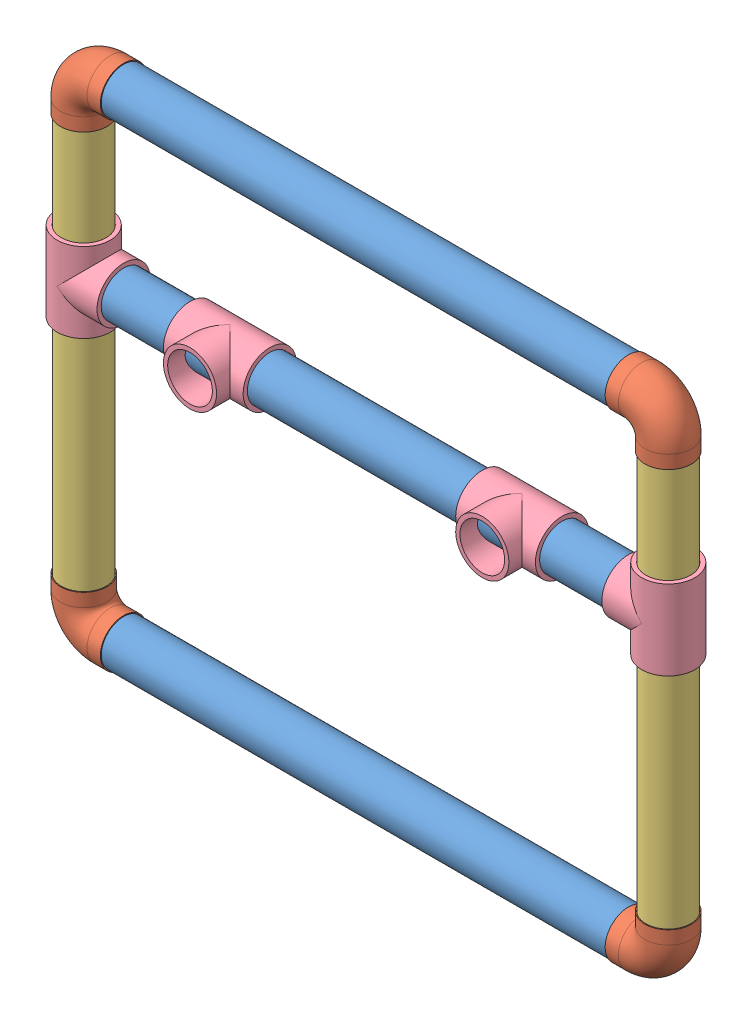
SolidWorks assembly structure_with_tube, configuration Default. Lengths in mm.
Overall size (307.13 254.74 41.21).
13 component instances, 4 part files, 26 mates.
Components (placement in the parent):
- PVC_tube_12in-1: PVC_tube_12in [Default] at (224.9643 139.1096 188.8412) size (254 21.34 21.34)
- PVC_90-1: PVC_90 [Default] at (-23.4538 156.2418 188.8412) size (30.16 30.16 22.23)
- PVC_90-2: PVC_90 [Default] at (220.532 157.3915 188.8412) x (0 1 0) z (0 0 1) size (30.16 30.16 22.23)
- PVC_tube_10in-1: PVC_tube_10in [Default] at (237.6643 151.8096 188.8412) x (0 -1 0) z (0.999303 0 -0.037318) size (203.2 21.34 21.34)
- PVC_90-3: PVC_90 [Default] at (219.3823 350.5774 188.8412) x (-1 0 0) z (0 0 1) size (30.16 30.16 22.23)
- PVC_tube_12in-2: PVC_tube_12in [Default] at (224.9643 367.7096 188.8412) x (1 0 0) z (0 -0.639566 -0.768737) size (254 21.34 21.34)
- PVC_90-4: PVC_90 [Default] at (-24.6035 349.4277 188.8412) x (0 -1 0) z (0 0 1) size (30.16 30.16 22.23)
- PVC_tube_10in-2: PVC_tube_10in [Default] at (-41.7357 355.0096 188.8412) x (0 1 0) z (0.64254 0 -0.766252) size (203.2 21.34 21.34)
- PVC_tee-1: PVC_tee [Default] at (-41.7357 283.3776 188.8412) x (0 1 0) z (0 0 -1) size (38.1 38.88 25.4)
- PVC_tee-2: PVC_tee [Default] at (237.6643 283.3776 188.8412) x (0 1 0) z (0 0 1) size (38.1 38.88 25.4)
- PVC_tee-4: PVC_tee [Default] at (28.1143 283.3776 188.8412) x (1 0 0) z (0 -1 0) size (38.1 38.88 25.4)
- PVC_tee-5: PVC_tee [Default] at (167.8143 283.3776 188.8412) x (1 0 0) z (0 -1 0) size (38.1 38.88 25.4)
- PVC_tube_12in-3: PVC_tube_12in [Default] at (231.0643 283.3776 188.8412) size (254 21.34 21.34)
Mates (geometry in assembly coordinates):
- Distance20: distance = 6.35 mm anti-aligned: plane of PVC_tube_10in-1 through (237.6643 355.0096 188.8412) normal (0 1 0); plane of PVC_90-3 through (237.6643 348.6596 188.8412) normal (0 -1 0)
- Distance14: distance = 6.35 mm anti-aligned: plane of PVC_tube_10in-2 through (-41.7357 151.8096 188.8412) normal (0 -1 0); plane of PVC_90-1 through (-41.7357 158.1596 188.8412) normal (0 1 0)
- Distance15: distance = 6.35 mm anti-aligned: plane of PVC_90-4 through (-41.7357 348.6596 188.8412) normal (0 -1 0); plane of PVC_tube_10in-2 through (-41.7357 355.0096 188.8412) normal (0 1 0)
- Distance16: distance = 6.35 mm anti-aligned: plane of PVC_tube_12in-2 through (-29.0357 367.7096 188.8412) normal (-1 0 0); plane of PVC_90-4 through (-22.6857 367.7096 188.8412) normal (1 0 0)
- Concentric3: concentric anti-aligned: circle of PVC_tube_12in-1; circle of PVC_90-1
- Distance17: distance = 6.35 mm anti-aligned: plane of PVC_tube_12in-1 through (-29.0357 139.1096 188.8412) normal (-1 0 0); plane of PVC_90-1 through (-22.6857 139.1096 188.8412) normal (1 0 0)
- Perpendicular1: perpendicular: plane of PVC_90-1 through (-41.7357 158.1596 188.8412) normal (0 1 0); line of assembly
- Concentric4: concentric anti-aligned: circle of PVC_90-1; circle of PVC_tube_10in-2
- Concentric5: concentric anti-aligned: circle of PVC_90-4; circle of PVC_tube_10in-2
- Concentric6: concentric anti-aligned: circle of PVC_tube_12in-2; circle of PVC_90-4
- Concentric7: concentric anti-aligned: circle of PVC_tube_10in-1; circle of PVC_90-3
- Distance18: distance = 6.35 mm anti-aligned: plane of PVC_90-3 through (218.6143 367.7096 188.8412) normal (-1 0 0); plane of PVC_tube_12in-2 through (224.9643 367.7096 188.8412) normal (1 0 0)
- Concentric8: concentric anti-aligned: circle of PVC_90-2; circle of PVC_tube_10in-1
- Concentric9: concentric anti-aligned: circle of PVC_tube_12in-1; circle of PVC_90-2
- Distance19: distance = 6.35 mm anti-aligned: plane of PVC_tube_10in-1 through (237.6643 151.8096 188.8412) normal (0 -1 0); plane of PVC_90-2 through (237.6643 158.1596 188.8412) normal (0 1 0)
- Concentric13: concentric anti-aligned: cylinder of PVC_tube_10in-1 through (237.6643 355.0096 188.8412) axis (0 -1 0) radius 10.668; circle of PVC_tee-2
- Perpendicular2: perpendicular: plane of PVC_90-2 through (237.6643 158.1596 188.8412) normal (0 1 0); line of assembly
- Perpendicular4: perpendicular: plane of PVC_tube_12in-2 through (224.9643 367.7096 188.8412) normal (1 0 0); line of assembly
- Coincident21: coincident anti-aligned: line of PVC_tee-1 through (-41.7357 283.3776 188.8412) axis (1 0 0); line of assembly
- Coincident22: coincident aligned: line of PVC_tee-2 through (237.6643 283.3776 188.8412) axis (-1 0 0); line of assembly
- Perpendicular5: perpendicular: line of PVC_tee-4 through (28.1143 283.3776 188.8412) axis (0 0 1); line of assembly
- Coincident24: coincident: point of PVC_tee-4; line of assembly
- Coincident25: coincident: point of PVC_tee-5; line of assembly
- Concentric14: concentric anti-aligned: circle of PVC_tube_12in-3; line of assembly
- Concentric15: concentric aligned: cylinder of PVC_tube_10in-2 through (-41.7357 151.8096 188.8412) axis (0 1 0) radius 10.668; circle of PVC_tee-1
- Distance21: distance = 0.25 mm anti-aligned: plane of PVC_tube_12in-3 through (-22.9357 283.3776 188.8412) normal (-1 0 0); plane of PVC_tee-1 through (-22.6857 283.3776 188.8412) normal (1 0 0)
